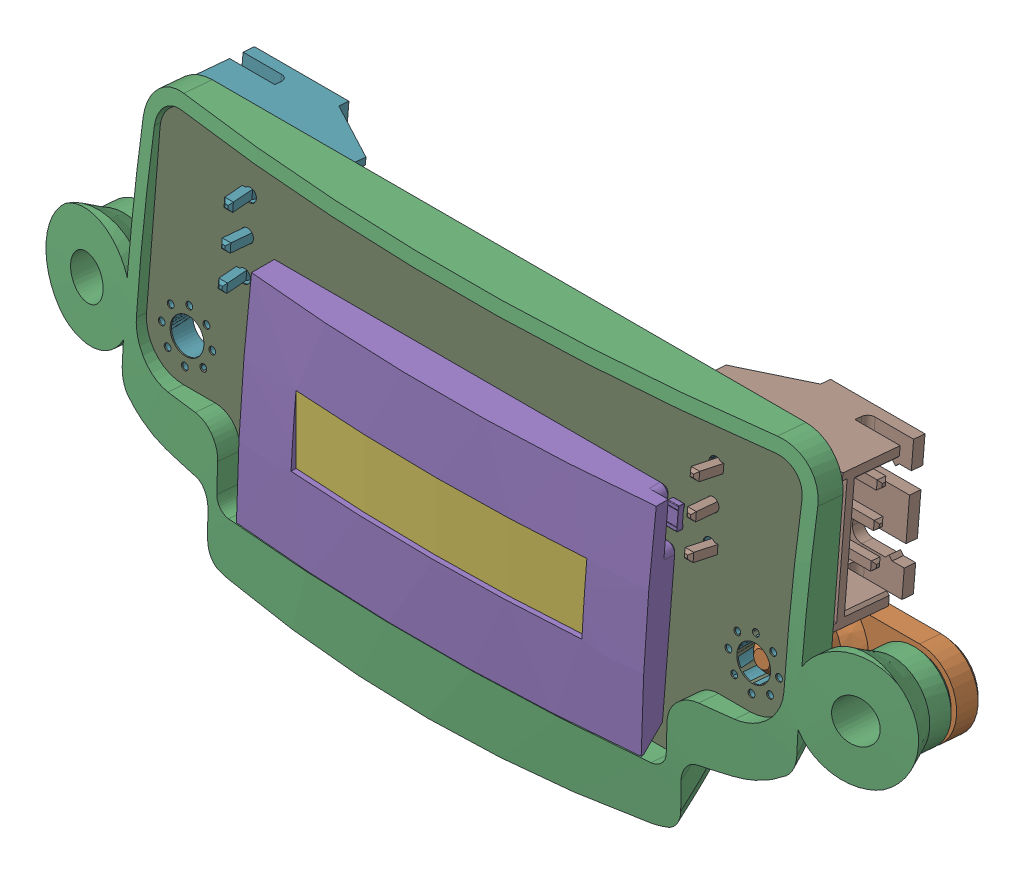
SolidWorks assembly rear_logic_lens_assembly2, configuration Default. Lengths in mm.
Overall size (65.11 27.36 12.04).
147 component instances, 6 part files, 6 mates.
Components (placement in the parent):
- rear_logic_lens-1: rear_logic_lens [Default] at origin size (65.11 27.36 9.89)
- head_logic_display_PCB-1: head_logic_display_PCB [Default] at (0 17.9829 140.1312) x (1 0 0) z (0 0.087156 0.996195) size (48 21.59 1.6) (hidden)
- head_logic_display-2: head_logic_display [Default] at (0 17.9916 140.2308) x (1 0 0) z (0 0.087156 0.996195) size (49.7 21.59 9.5)
  - head_logic_display(2)-1: head_logic_display(2) [Default] at origin size (49.7 21.59 9.5)
    - LED-SMD_4P-L1.0-W1.0-TL_XL-1010RGBC-WS2812B-1: LED-SMD_4P-L1.0-W1.0-TL_XL-1010RGBC-WS2812B [Default] at (-7.892 -7.295 1.65) x (0 1 0) z (0 0 1) size (1 1 0.81)
      - LED-SMD_4P-L1.0-W1.0-TL_XL-1010RGBC-WS2812B-0-1: LED-SMD_4P-L1.0-W1.0-TL_XL-1010RGBC-WS2812B-0 [Default] at origin size (1 1 0.81)
    - C_0402_1005Metric-1: C_0402_1005Metric [Default] at (-10.206 3.245 1.65) x (-1 0 0) z (0 0 1) size (1 0.5 0.5)
      - C_0402_1005Metric-1-1: C_0402_1005Metric-1 [Default] at origin size (1 0.5 0.5)
    - LED-SMD_4P-L1.0-W1.0-TL_XL-1010RGBC-WS2812B-2: LED-SMD_4P-L1.0-W1.0-TL_XL-1010RGBC-WS2812B [Default] at (9.7 -2.705 1.65) size (1 1 0.81)
      - LED-SMD_4P-L1.0-W1.0-TL_XL-1010RGBC-WS2812B-0-1: LED-SMD_4P-L1.0-W1.0-TL_XL-1010RGBC-WS2812B-0 [Default] at origin size (1 1 0.81)
    - C_0402_1005Metric-2: C_0402_1005Metric [Default] at (7.826 -5.905 1.65) x (-1 0 0) z (0 0 1) size (1 0.5 0.5)
      - C_0402_1005Metric-1-1: C_0402_1005Metric-1 [Default] at origin size (1 0.5 0.5)
    - LED-SMD_4P-L1.0-W1.0-TL_XL-1010RGBC-WS2812B-3: LED-SMD_4P-L1.0-W1.0-TL_XL-1010RGBC-WS2812B [Default] at (-5.638 -7.295 1.65) size (1 1 0.81)
      - LED-SMD_4P-L1.0-W1.0-TL_XL-1010RGBC-WS2812B-0-1: LED-SMD_4P-L1.0-W1.0-TL_XL-1010RGBC-WS2812B-0 [Default] at origin size (1 1 0.81)
    - LED-SMD_4P-L1.0-W1.0-TL_XL-1010RGBC-WS2812B-4: LED-SMD_4P-L1.0-W1.0-TL_XL-1010RGBC-WS2812B [Default] at (1.084 -2.705 1.65) size (1 1 0.81)
      - LED-SMD_4P-L1.0-W1.0-TL_XL-1010RGBC-WS2812B-0-1: LED-SMD_4P-L1.0-W1.0-TL_XL-1010RGBC-WS2812B-0 [Default] at origin size (1 1 0.81)
    - LED-SMD_4P-L1.0-W1.0-TL_XL-1010RGBC-WS2812B-5: LED-SMD_4P-L1.0-W1.0-TL_XL-1010RGBC-WS2812B [Default] at (3.378 1.875 1.65) size (1 1 0.81)
      - LED-SMD_4P-L1.0-W1.0-TL_XL-1010RGBC-WS2812B-0-1: LED-SMD_4P-L1.0-W1.0-TL_XL-1010RGBC-WS2812B-0 [Default] at origin size (1 1 0.81)
    - LED-SMD_4P-L1.0-W1.0-TL_XL-1010RGBC-WS2812B-6: LED-SMD_4P-L1.0-W1.0-TL_XL-1010RGBC-WS2812B [Default] at (-1.07 -2.705 1.65) x (0 1 0) z (0 0 1) size (1 1 0.81)
      - LED-SMD_4P-L1.0-W1.0-TL_XL-1010RGBC-WS2812B-0-1: LED-SMD_4P-L1.0-W1.0-TL_XL-1010RGBC-WS2812B-0 [Default] at origin size (1 1 0.81)
    - LED-SMD_4P-L1.0-W1.0-TL_XL-1010RGBC-WS2812B-7: LED-SMD_4P-L1.0-W1.0-TL_XL-1010RGBC-WS2812B [Default] at (-7.532 -2.705 1.65) size (1 1 0.81)
      - LED-SMD_4P-L1.0-W1.0-TL_XL-1010RGBC-WS2812B-0-1: LED-SMD_4P-L1.0-W1.0-TL_XL-1010RGBC-WS2812B-0 [Default] at origin size (1 1 0.81)
    - LED-SMD_4P-L1.0-W1.0-TL_XL-1010RGBC-WS2812B-8: LED-SMD_4P-L1.0-W1.0-TL_XL-1010RGBC-WS2812B [Default] at (12.394 1.875 1.65) size (1 1 0.81)
      - LED-SMD_4P-L1.0-W1.0-TL_XL-1010RGBC-WS2812B-0-1: LED-SMD_4P-L1.0-W1.0-TL_XL-1010RGBC-WS2812B-0 [Default] at origin size (1 1 0.81)
    - LED-SMD_4P-L1.0-W1.0-TL_XL-1010RGBC-WS2812B-9: LED-SMD_4P-L1.0-W1.0-TL_XL-1010RGBC-WS2812B [Default] at (5.632 -7.295 1.65) x (0 1 0) z (0 0 1) size (1 1 0.81)
      - LED-SMD_4P-L1.0-W1.0-TL_XL-1010RGBC-WS2812B-0-1: LED-SMD_4P-L1.0-W1.0-TL_XL-1010RGBC-WS2812B-0 [Default] at origin size (1 1 0.81)
    - C_0402_1005Metric-3: C_0402_1005Metric [Default] at (-12.34 -5.905 1.65) size (1 0.5 0.5)
      - C_0402_1005Metric-1-1: C_0402_1005Metric-1 [Default] at origin size (1 0.5 0.5)
    - LED-SMD_4P-L1.0-W1.0-TL_XL-1010RGBC-WS2812B-10: LED-SMD_4P-L1.0-W1.0-TL_XL-1010RGBC-WS2812B [Default] at (-7.892 1.875 1.65) x (0 1 0) z (0 0 1) size (1 1 0.81)
      - LED-SMD_4P-L1.0-W1.0-TL_XL-1010RGBC-WS2812B-0-1: LED-SMD_4P-L1.0-W1.0-TL_XL-1010RGBC-WS2812B-0 [Default] at origin size (1 1 0.81)
    - LED-SMD_4P-L1.0-W1.0-TL_XL-1010RGBC-WS2812B-11: LED-SMD_4P-L1.0-W1.0-TL_XL-1010RGBC-WS2812B [Default] at (3.238 -2.705 1.65) x (0 1 0) z (0 0 1) size (1 1 0.81)
      - LED-SMD_4P-L1.0-W1.0-TL_XL-1010RGBC-WS2812B-0-1: LED-SMD_4P-L1.0-W1.0-TL_XL-1010RGBC-WS2812B-0 [Default] at origin size (1 1 0.81)
    - R_0603_1608Metric-1: R_0603_1608Metric [Default] at (14.9 3.645 1.65) x (0 -1 0) z (0 0 1) size (1.6 0.8 0.45)
      - R_0603_1608Metric-2-1: R_0603_1608Metric-2 [Default] at origin size (1.6 0.8 0.45)
    - C_0402_1005Metric-4: C_0402_1005Metric [Default] at (-5.318 -1.305 1.65) size (1 0.5 0.5)
      - C_0402_1005Metric-1-1: C_0402_1005Metric-1 [Default] at origin size (1 0.5 0.5)
    - C_0402_1005Metric-5: C_0402_1005Metric [Default] at (-9.626 -1.305 1.65) size (1 0.5 0.5)
      - C_0402_1005Metric-1-1: C_0402_1005Metric-1 [Default] at origin size (1 0.5 0.5)
    - LED-SMD_4P-L1.0-W1.0-TL_XL-1010RGBC-WS2812B-12: LED-SMD_4P-L1.0-W1.0-TL_XL-1010RGBC-WS2812B [Default] at (-5.638 1.875 1.65) size (1 1 0.81)
      - LED-SMD_4P-L1.0-W1.0-TL_XL-1010RGBC-WS2812B-0-1: LED-SMD_4P-L1.0-W1.0-TL_XL-1010RGBC-WS2812B-0 [Default] at origin size (1 1 0.81)
    - LED-SMD_4P-L1.0-W1.0-TL_XL-1010RGBC-WS2812B-13: LED-SMD_4P-L1.0-W1.0-TL_XL-1010RGBC-WS2812B [Default] at (-1.13 -7.295 1.65) size (1 1 0.81)
      - LED-SMD_4P-L1.0-W1.0-TL_XL-1010RGBC-WS2812B-0-1: LED-SMD_4P-L1.0-W1.0-TL_XL-1010RGBC-WS2812B-0 [Default] at origin size (1 1 0.81)
    - C_0402_1005Metric-6: C_0402_1005Metric [Default] at (7.826 3.245 1.65) x (-1 0 0) z (0 0 1) size (1 0.5 0.5)
      - C_0402_1005Metric-1-1: C_0402_1005Metric-1 [Default] at origin size (1 0.5 0.5)
    - LED-SMD_4P-L1.0-W1.0-TL_XL-1010RGBC-WS2812B-14: LED-SMD_4P-L1.0-W1.0-TL_XL-1010RGBC-WS2812B [Default] at (-12.4 1.875 1.65) x (0 1 0) z (0 0 1) size (1 1 0.81)
      - LED-SMD_4P-L1.0-W1.0-TL_XL-1010RGBC-WS2812B-0-1: LED-SMD_4P-L1.0-W1.0-TL_XL-1010RGBC-WS2812B-0 [Default] at origin size (1 1 0.81)
    - C_0402_1005Metric-7: C_0402_1005Metric [Default] at (5.332 -1.305 1.65) x (-1 0 0) z (0 0 1) size (1 0.5 0.5)
      - C_0402_1005Metric-1-1: C_0402_1005Metric-1 [Default] at origin size (1 0.5 0.5)
    - C_0402_1005Metric-8: C_0402_1005Metric [Default] at (5.692 3.245 1.65) size (1 0.5 0.5)
      - C_0402_1005Metric-1-1: C_0402_1005Metric-1 [Default] at origin size (1 0.5 0.5)
    - LED-SMD_4P-L1.0-W1.0-TL_XL-1010RGBC-WS2812B-15: LED-SMD_4P-L1.0-W1.0-TL_XL-1010RGBC-WS2812B [Default] at (5.632 1.875 1.65) x (0 1 0) z (0 0 1) size (1 1 0.81)
      - LED-SMD_4P-L1.0-W1.0-TL_XL-1010RGBC-WS2812B-0-1: LED-SMD_4P-L1.0-W1.0-TL_XL-1010RGBC-WS2812B-0 [Default] at origin size (1 1 0.81)
    - LED-SMD_4P-L1.0-W1.0-TL_XL-1010RGBC-WS2812B-16: LED-SMD_4P-L1.0-W1.0-TL_XL-1010RGBC-WS2812B [Default] at (7.546 -2.705 1.65) x (0 1 0) z (0 0 1) size (1 1 0.81)
      - LED-SMD_4P-L1.0-W1.0-TL_XL-1010RGBC-WS2812B-0-1: LED-SMD_4P-L1.0-W1.0-TL_XL-1010RGBC-WS2812B-0 [Default] at origin size (1 1 0.81)
    - C_0402_1005Metric-9: C_0402_1005Metric [Default] at (1.184 -5.905 1.65) size (1 0.5 0.5)
      - C_0402_1005Metric-1-1: C_0402_1005Metric-1 [Default] at origin size (1 0.5 0.5)
    - LED-SMD_4P-L1.0-W1.0-TL_XL-1010RGBC-WS2812B-17: LED-SMD_4P-L1.0-W1.0-TL_XL-1010RGBC-WS2812B [Default] at (-3.224 -2.705 1.65) size (1 1 0.81)
      - LED-SMD_4P-L1.0-W1.0-TL_XL-1010RGBC-WS2812B-0-1: LED-SMD_4P-L1.0-W1.0-TL_XL-1010RGBC-WS2812B-0 [Default] at origin size (1 1 0.81)
    - C_0402_1005Metric-10: C_0402_1005Metric [Default] at (-7.832 -5.905 1.65) size (1 0.5 0.5)
      - C_0402_1005Metric-1-1: C_0402_1005Metric-1 [Default] at origin size (1 0.5 0.5)
    - C_0402_1005Metric-11: C_0402_1005Metric [Default] at (3.318 -5.905 1.65) x (-1 0 0) z (0 0 1) size (1 0.5 0.5)
      - C_0402_1005Metric-1-1: C_0402_1005Metric-1 [Default] at origin size (1 0.5 0.5)
    - C_0402_1005Metric-12: C_0402_1005Metric [Default] at (-10.206 -5.905 1.65) x (-1 0 0) z (0 0 1) size (1 0.5 0.5)
      - C_0402_1005Metric-1-1: C_0402_1005Metric-1 [Default] at origin size (1 0.5 0.5)
    - LED-SMD_4P-L1.0-W1.0-TL_XL-1010RGBC-WS2812B-18: LED-SMD_4P-L1.0-W1.0-TL_XL-1010RGBC-WS2812B [Default] at (-5.378 -2.705 1.65) x (0 1 0) z (0 0 1) size (1 1 0.81)
      - LED-SMD_4P-L1.0-W1.0-TL_XL-1010RGBC-WS2812B-0-1: LED-SMD_4P-L1.0-W1.0-TL_XL-1010RGBC-WS2812B-0 [Default] at origin size (1 1 0.81)
    - LED-SMD_4P-L1.0-W1.0-TL_XL-1010RGBC-WS2812B-19: LED-SMD_4P-L1.0-W1.0-TL_XL-1010RGBC-WS2812B [Default] at (5.392 -2.705 1.65) size (1 1 0.81)
      - LED-SMD_4P-L1.0-W1.0-TL_XL-1010RGBC-WS2812B-0-1: LED-SMD_4P-L1.0-W1.0-TL_XL-1010RGBC-WS2812B-0 [Default] at origin size (1 1 0.81)
    - LED-SMD_4P-L1.0-W1.0-TL_XL-1010RGBC-WS2812B-20: LED-SMD_4P-L1.0-W1.0-TL_XL-1010RGBC-WS2812B [Default] at (1.124 -7.295 1.65) x (0 1 0) z (0 0 1) size (1 1 0.81)
      - LED-SMD_4P-L1.0-W1.0-TL_XL-1010RGBC-WS2812B-0-1: LED-SMD_4P-L1.0-W1.0-TL_XL-1010RGBC-WS2812B-0 [Default] at origin size (1 1 0.81)
    - C_0402_1005Metric-13: C_0402_1005Metric [Default] at (-5.698 3.245 1.65) x (-1 0 0) z (0 0 1) size (1 0.5 0.5)
      - C_0402_1005Metric-1-1: C_0402_1005Metric-1 [Default] at origin size (1 0.5 0.5)
    - C_0402_1005Metric-14: C_0402_1005Metric [Default] at (5.692 -5.905 1.65) size (1 0.5 0.5)
      - C_0402_1005Metric-1-1: C_0402_1005Metric-1 [Default] at origin size (1 0.5 0.5)
    - C_0402_1005Metric-15: C_0402_1005Metric [Default] at (12.334 3.245 1.65) x (-1 0 0) z (0 0 1) size (1 0.5 0.5)
      - C_0402_1005Metric-1-1: C_0402_1005Metric-1 [Default] at origin size (1 0.5 0.5)
    - C_0402_1005Metric-16: C_0402_1005Metric [Default] at (3.298 -1.305 1.65) size (1 0.5 0.5)
      - C_0402_1005Metric-1-1: C_0402_1005Metric-1 [Default] at origin size (1 0.5 0.5)
    - C_0402_1005Metric-17: C_0402_1005Metric [Default] at (-3.284 -1.305 1.65) x (-1 0 0) z (0 0 1) size (1 0.5 0.5)
      - C_0402_1005Metric-1-1: C_0402_1005Metric-1 [Default] at origin size (1 0.5 0.5)
    - LED-SMD_4P-L1.0-W1.0-TL_XL-1010RGBC-WS2812B-21: LED-SMD_4P-L1.0-W1.0-TL_XL-1010RGBC-WS2812B [Default] at (-3.384 -7.295 1.65) x (0 1 0) z (0 0 1) size (1 1 0.81)
      - LED-SMD_4P-L1.0-W1.0-TL_XL-1010RGBC-WS2812B-0-1: LED-SMD_4P-L1.0-W1.0-TL_XL-1010RGBC-WS2812B-0 [Default] at origin size (1 1 0.81)
    - LED-SMD_4P-L1.0-W1.0-TL_XL-1010RGBC-WS2812B-22: LED-SMD_4P-L1.0-W1.0-TL_XL-1010RGBC-WS2812B [Default] at (1.124 1.875 1.65) x (0 1 0) z (0 0 1) size (1 1 0.81)
      - LED-SMD_4P-L1.0-W1.0-TL_XL-1010RGBC-WS2812B-0-1: LED-SMD_4P-L1.0-W1.0-TL_XL-1010RGBC-WS2812B-0 [Default] at origin size (1 1 0.81)
    - LED-SMD_4P-L1.0-W1.0-TL_XL-1010RGBC-WS2812B-23: LED-SMD_4P-L1.0-W1.0-TL_XL-1010RGBC-WS2812B [Default] at (10.14 -7.295 1.65) x (0 1 0) z (0 0 1) size (1 1 0.81)
      - LED-SMD_4P-L1.0-W1.0-TL_XL-1010RGBC-WS2812B-0-1: LED-SMD_4P-L1.0-W1.0-TL_XL-1010RGBC-WS2812B-0 [Default] at origin size (1 1 0.81)
    - LED-SMD_4P-L1.0-W1.0-TL_XL-1010RGBC-WS2812B-24: LED-SMD_4P-L1.0-W1.0-TL_XL-1010RGBC-WS2812B [Default] at (-12.4 -7.295 1.65) x (0 1 0) z (0 0 1) size (1 1 0.81)
      - LED-SMD_4P-L1.0-W1.0-TL_XL-1010RGBC-WS2812B-0-1: LED-SMD_4P-L1.0-W1.0-TL_XL-1010RGBC-WS2812B-0 [Default] at origin size (1 1 0.81)
    - LED-SMD_4P-L1.0-W1.0-TL_XL-1010RGBC-WS2812B-25: LED-SMD_4P-L1.0-W1.0-TL_XL-1010RGBC-WS2812B [Default] at (-10.146 -7.295 1.65) size (1 1 0.81)
      - LED-SMD_4P-L1.0-W1.0-TL_XL-1010RGBC-WS2812B-0-1: LED-SMD_4P-L1.0-W1.0-TL_XL-1010RGBC-WS2812B-0 [Default] at origin size (1 1 0.81)
    - C_0402_1005Metric-18: C_0402_1005Metric [Default] at (-12.34 3.245 1.65) size (1 0.5 0.5)
      - C_0402_1005Metric-1-1: C_0402_1005Metric-1 [Default] at origin size (1 0.5 0.5)
    - C_0402_1005Metric-19: C_0402_1005Metric [Default] at (3.318 3.245 1.65) x (-1 0 0) z (0 0 1) size (1 0.5 0.5)
      - C_0402_1005Metric-1-1: C_0402_1005Metric-1 [Default] at origin size (1 0.5 0.5)
    - C_0402_1005Metric-20: C_0402_1005Metric [Default] at (-1.19 3.245 1.65) x (-1 0 0) z (0 0 1) size (1 0.5 0.5)
      - C_0402_1005Metric-1-1: C_0402_1005Metric-1 [Default] at origin size (1 0.5 0.5)
    - C_0402_1005Metric-21: C_0402_1005Metric [Default] at (-3.324 3.245 1.65) size (1 0.5 0.5)
      - C_0402_1005Metric-1-1: C_0402_1005Metric-1 [Default] at origin size (1 0.5 0.5)
    - C_0402_1005Metric-22: C_0402_1005Metric [Default] at (-7.592 -1.305 1.65) x (-1 0 0) z (0 0 1) size (1 0.5 0.5)
      - C_0402_1005Metric-1-1: C_0402_1005Metric-1 [Default] at origin size (1 0.5 0.5)
    - C_0402_1005Metric-23: C_0402_1005Metric [Default] at (9.64 -1.305 1.65) x (-1 0 0) z (0 0 1) size (1 0.5 0.5)
      - C_0402_1005Metric-1-1: C_0402_1005Metric-1 [Default] at origin size (1 0.5 0.5)
    - C_0402_1005Metric-24: C_0402_1005Metric [Default] at (-1.01 -1.305 1.65) size (1 0.5 0.5)
      - C_0402_1005Metric-1-1: C_0402_1005Metric-1 [Default] at origin size (1 0.5 0.5)
    - LED-SMD_4P-L1.0-W1.0-TL_XL-1010RGBC-WS2812B-26: LED-SMD_4P-L1.0-W1.0-TL_XL-1010RGBC-WS2812B [Default] at (-9.686 -2.705 1.65) x (0 1 0) z (0 0 1) size (1 1 0.81)
      - LED-SMD_4P-L1.0-W1.0-TL_XL-1010RGBC-WS2812B-0-1: LED-SMD_4P-L1.0-W1.0-TL_XL-1010RGBC-WS2812B-0 [Default] at origin size (1 1 0.81)
    - LED-SMD_4P-L1.0-W1.0-TL_XL-1010RGBC-WS2812B-27: LED-SMD_4P-L1.0-W1.0-TL_XL-1010RGBC-WS2812B [Default] at (12.394 -7.295 1.65) size (1 1 0.81)
      - LED-SMD_4P-L1.0-W1.0-TL_XL-1010RGBC-WS2812B-0-1: LED-SMD_4P-L1.0-W1.0-TL_XL-1010RGBC-WS2812B-0 [Default] at origin size (1 1 0.81)
    - C_0402_1005Metric-25: C_0402_1005Metric [Default] at (7.606 -1.305 1.65) size (1 0.5 0.5)
      - C_0402_1005Metric-1-1: C_0402_1005Metric-1 [Default] at origin size (1 0.5 0.5)
    - LED-SMD_4P-L1.0-W1.0-TL_XL-1010RGBC-WS2812B-28: LED-SMD_4P-L1.0-W1.0-TL_XL-1010RGBC-WS2812B [Default] at (-10.146 1.875 1.65) size (1 1 0.81)
      - LED-SMD_4P-L1.0-W1.0-TL_XL-1010RGBC-WS2812B-0-1: LED-SMD_4P-L1.0-W1.0-TL_XL-1010RGBC-WS2812B-0 [Default] at origin size (1 1 0.81)
    - C_0402_1005Metric-26: C_0402_1005Metric [Default] at (-1.19 -5.905 1.65) x (-1 0 0) z (0 0 1) size (1 0.5 0.5)
      - C_0402_1005Metric-1-1: C_0402_1005Metric-1 [Default] at origin size (1 0.5 0.5)
    - LED-SMD_4P-L1.0-W1.0-TL_XL-1010RGBC-WS2812B-29: LED-SMD_4P-L1.0-W1.0-TL_XL-1010RGBC-WS2812B [Default] at (-3.384 1.875 1.65) x (0 1 0) z (0 0 1) size (1 1 0.81)
      - LED-SMD_4P-L1.0-W1.0-TL_XL-1010RGBC-WS2812B-0-1: LED-SMD_4P-L1.0-W1.0-TL_XL-1010RGBC-WS2812B-0 [Default] at origin size (1 1 0.81)
    - LED-SMD_4P-L1.0-W1.0-TL_XL-1010RGBC-WS2812B-30: LED-SMD_4P-L1.0-W1.0-TL_XL-1010RGBC-WS2812B [Default] at (7.886 -7.295 1.65) size (1 1 0.81)
      - LED-SMD_4P-L1.0-W1.0-TL_XL-1010RGBC-WS2812B-0-1: LED-SMD_4P-L1.0-W1.0-TL_XL-1010RGBC-WS2812B-0 [Default] at origin size (1 1 0.81)
    - C_0402_1005Metric-27: C_0402_1005Metric [Default] at (10.2 3.245 1.65) size (1 0.5 0.5)
      - C_0402_1005Metric-1-1: C_0402_1005Metric-1 [Default] at origin size (1 0.5 0.5)
    - C_0402_1005Metric-28: C_0402_1005Metric [Default] at (12.334 -5.905 1.65) x (-1 0 0) z (0 0 1) size (1 0.5 0.5)
      - C_0402_1005Metric-1-1: C_0402_1005Metric-1 [Default] at origin size (1 0.5 0.5)
    - LED-SMD_4P-L1.0-W1.0-TL_XL-1010RGBC-WS2812B-31: LED-SMD_4P-L1.0-W1.0-TL_XL-1010RGBC-WS2812B [Default] at (-1.13 1.875 1.65) size (1 1 0.81)
      - LED-SMD_4P-L1.0-W1.0-TL_XL-1010RGBC-WS2812B-0-1: LED-SMD_4P-L1.0-W1.0-TL_XL-1010RGBC-WS2812B-0 [Default] at origin size (1 1 0.81)
    - C_0402_1005Metric-29: C_0402_1005Metric [Default] at (-5.698 -5.905 1.65) x (-1 0 0) z (0 0 1) size (1 0.5 0.5)
      - C_0402_1005Metric-1-1: C_0402_1005Metric-1 [Default] at origin size (1 0.5 0.5)
    - C_0402_1005Metric-30: C_0402_1005Metric [Default] at (-7.832 3.245 1.65) size (1 0.5 0.5)
      - C_0402_1005Metric-1-1: C_0402_1005Metric-1 [Default] at origin size (1 0.5 0.5)
    - C_0402_1005Metric-31: C_0402_1005Metric [Default] at (1.024 -1.305 1.65) x (-1 0 0) z (0 0 1) size (1 0.5 0.5)
      - C_0402_1005Metric-1-1: C_0402_1005Metric-1 [Default] at origin size (1 0.5 0.5)
    - C_0402_1005Metric-32: C_0402_1005Metric [Default] at (1.184 3.245 1.65) size (1 0.5 0.5)
      - C_0402_1005Metric-1-1: C_0402_1005Metric-1 [Default] at origin size (1 0.5 0.5)
    - LED-SMD_4P-L1.0-W1.0-TL_XL-1010RGBC-WS2812B-32: LED-SMD_4P-L1.0-W1.0-TL_XL-1010RGBC-WS2812B [Default] at (10.14 1.875 1.65) x (0 1 0) z (0 0 1) size (1 1 0.81)
      - LED-SMD_4P-L1.0-W1.0-TL_XL-1010RGBC-WS2812B-0-1: LED-SMD_4P-L1.0-W1.0-TL_XL-1010RGBC-WS2812B-0 [Default] at origin size (1 1 0.81)
    - C_0402_1005Metric-33: C_0402_1005Metric [Default] at (-3.324 -5.905 1.65) size (1 0.5 0.5)
      - C_0402_1005Metric-1-1: C_0402_1005Metric-1 [Default] at origin size (1 0.5 0.5)
    - LED-SMD_4P-L1.0-W1.0-TL_XL-1010RGBC-WS2812B-33: LED-SMD_4P-L1.0-W1.0-TL_XL-1010RGBC-WS2812B [Default] at (7.886 1.875 1.65) size (1 1 0.81)
      - LED-SMD_4P-L1.0-W1.0-TL_XL-1010RGBC-WS2812B-0-1: LED-SMD_4P-L1.0-W1.0-TL_XL-1010RGBC-WS2812B-0 [Default] at origin size (1 1 0.81)
    - LED-SMD_4P-L1.0-W1.0-TL_XL-1010RGBC-WS2812B-34: LED-SMD_4P-L1.0-W1.0-TL_XL-1010RGBC-WS2812B [Default] at (3.378 -7.295 1.65) size (1 1 0.81)
      - LED-SMD_4P-L1.0-W1.0-TL_XL-1010RGBC-WS2812B-0-1: LED-SMD_4P-L1.0-W1.0-TL_XL-1010RGBC-WS2812B-0 [Default] at origin size (1 1 0.81)
    - C_0402_1005Metric-34: C_0402_1005Metric [Default] at (10.2 -5.905 1.65) size (1 0.5 0.5)
      - C_0402_1005Metric-1-1: C_0402_1005Metric-1 [Default] at origin size (1 0.5 0.5)
    - JST_XH_S3B-XH-A-1_1x03_P2.50mm_Horizontal-1: JST_XH_S3B-XH-A-1_1x03_P2.50mm_Horizontal [Default] at (-17.25 2.795 -0.05) x (0 1 0) z (0 0 -1) size (9.9 11.5 9.5)
      - JST_S3B_XH_A_1-1: JST_S3B_XH_A_1 [Default] at origin size (9.9 11.5 9.5)
    - JST_XH_S3B-XH-A-1_1x03_P2.50mm_Horizontal-2: JST_XH_S3B-XH-A-1_1x03_P2.50mm_Horizontal [Default] at (17.25 7.795 -0.05) x (0 -1 0) z (0 0 -1) size (9.9 11.5 9.5)
      - JST_S3B_XH_A_1-1: JST_S3B_XH_A_1 [Default] at origin size (9.9 11.5 9.5)
    - head_logic_display_PCB-1: head_logic_display_PCB [Default] at origin size (48 21.59 1.6)
Mates (geometry in assembly coordinates):
- Coincident12: coincident anti-aligned: plane of rear_logic_lens_thin-1 through (-15.655 8.7881 158.893) normal (0 0.996195 -0.087156); plane of head_logic_display-2/head_logic_display(2)-1/head_logic_display_PCB-1 through (15.6542 7.2377 141.1717) normal (0 -0.996195 0.087156)
- Coincident13: coincident anti-aligned: plane of rear_logic_lens_thin-1 through (24 16.8473 158.1879) normal (-1 0 0); plane of head_logic_display-2/head_logic_display(2)-1/head_logic_display_PCB-1 through (24 26.7531 139.4643) normal (1 0 0)
- Coincident14: coincident aligned: plane of rear_logic_lens_thin-1 through (22 26.9623 139.446) normal (0 -0.087156 -0.996195); plane of head_logic_display-2/head_logic_display(2)-1/head_logic_display_PCB-1 through (0 17.9916 140.2308) normal (0 -0.087156 -0.996195)
- Coincident15: coincident anti-aligned: plane of rear_logic_lens_thin-1 through (-15.655 8.7881 158.893) normal (0 0.996195 -0.087156); plane of head_logic_display_PCB-1 through (15.6542 7.229 141.0721) normal (0 -0.996195 0.087156)
- Coincident16: coincident anti-aligned: plane of rear_logic_lens_thin-1 through (24 16.8473 158.1879) normal (-1 0 0); plane of head_logic_display_PCB-1 through (24 26.7444 139.3647) normal (1 0 0)
- Distance1: distance = 0.1 mm aligned: plane of rear_logic_lens_thin-1 through (22 26.9623 139.446) normal (0 -0.087156 -0.996195); plane of head_logic_display_PCB-1 through (0 17.9829 140.1312) normal (0 -0.087156 -0.996195)
